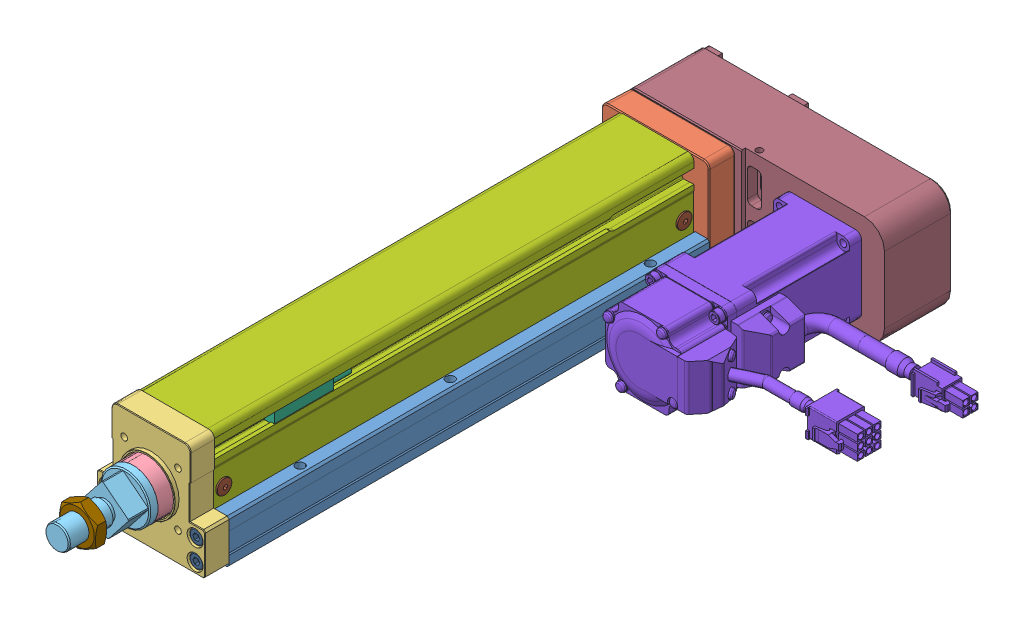
SolidWorks assembly CFY5-BR-100W, configuration Default. Lengths in mm.
Overall size (197.79 55.75 350).
25 component instances, 14 part files, 57 mates.
Components (placement in the parent):
- 底座GY5^CFY5-BR-100W-1: 底座GY5^CFY5-BR-100W [默认] at (172.2343 500.0265 205.4117) x (1 0 0) z (0 -1 0) size (54 240 25) (virtual)
- 丝杆座板GY5^CFY5-BR-100W-1: 丝杆座板GY5^CFY5-BR-100W [默认] at (172.2343 515.5765 191.9117) size (54.09 55.09 28) (virtual)
- 轴承座Y5^CFY5-BR-100W-1: 轴承座Y5^CFY5-BR-100W [Default] at (172.2343 516.7765 445.4117) size (54 54 22) (virtual)
- 推杆Y5^CFY5-BR-100W-1: 推杆Y5^CFY5-BR-100W [Default] at (172.2343 516.7765 316.4117) x (-0.030388 -0.999538 0) z (-0.999538 0.030388 0) size (25 150 25) (virtual)
- 螺纹连接头Y5^CFY5-BR-100W-1: 螺纹连接头Y5^CFY5-BR-100W [Default] at (172.2343 516.7765 470.4117) x (-0.620248 -0.784406 0) z (0 0 -1) size (25 25 47) (virtual)
- 磁性感应开关^CFY5-BR-100W-2: 磁性感应开关^CFY5-BR-100W [默认] at (153.1454 533.4018 308.9117) x (-1 0 0) z (0 0 -1) size (5 6.3 39.5) (virtual)
- 上盖Y5^CFY5-BR-100W-1: 上盖Y5^CFY5-BR-100W [Default] at (153.6454 513.9765 205.4117) size (38.57 34 240) (virtual)
- 松下100W电机MSMF012L1U2^CFY5-BR-100W-1: 松下100W电机MSMF012L1U2^CFY5-BR-100W [默认] at (241.2343 516.7765 190.4117) x (0 0 -1) z (0 -1 0) size (118.87 120.84 38.2) (virtual)
- 磁性感应开关^CFY5-BR-100W-3: 磁性感应开关^CFY5-BR-100W [默认] at (153.1454 533.4018 269.4117) x (-1 0 0) z (0 0 -1) size (5 6.3 39.5) (virtual)
- 磁性感应开关^CFY5-BR-100W-4: 磁性感应开关^CFY5-BR-100W [默认] at (191.3174 533.4018 385.4117) x (1 0 0) z (0 0 -1) size (5 6.3 39.5) (virtual)
- 六角薄螺母M12×1.25^CFY5-BR-100W-1: 六角薄螺母M12×1.25^CFY5-BR-100W [默认] at (172.2343 516.7765 494.4117) x (0.828588 -0.559859 0) z (0 0 1) size (20.78 18 6) (virtual)
- hexagon socket head cap screws gb-6: hexagon socket head cap screws gb [GB_FASTENER_SCREWS_HSHCS M4X12-N] at (194.2343 504.2765 456.8117) x (0 0 -1) z (1 0 0) size (16 7 7)
- hexagon socket head cap screws gb-7: hexagon socket head cap screws gb [GB_FASTENER_SCREWS_HSHCS M4X12-N] at (194.2343 493.7765 456.8117) x (0 0 -1) z (1 0 0) size (16 7 7)
- hexagon socket head cap screws gb-8: hexagon socket head cap screws gb [GB_FASTENER_SCREWS_HSHCS M4X12-N] at (150.2343 493.7765 456.8117) x (0 0 -1) z (1 0 0) size (16 7 7)
- hexagon socket head cap screws gb-9: hexagon socket head cap screws gb [GB_FASTENER_SCREWS_HSHCS M4X12-N] at (150.2343 504.2765 456.8117) x (0 0 -1) z (1 0 0) size (16 7 7)
- 内六角螺丝M3X5^CFY5-BR-100W-1: 内六角螺丝M3X5^CFY5-BR-100W [默认] at (186.1785 516.7765 210.4117) x (0 -1 0) z (0 0 1) size (7.5 6.19 7.5) (virtual)
- 内六角螺丝M3X5^CFY5-BR-100W-2: 内六角螺丝M3X5^CFY5-BR-100W [默认] at (186.1785 516.7765 440.4117) x (0 -0.21215 -0.977237) z (0 -0.977237 0.21215) size (7.5 6.19 7.5) (virtual)
- 内六角螺丝M3X5^CFY5-BR-100W-3: 内六角螺丝M3X5^CFY5-BR-100W [默认] at (158.2843 516.7765 440.4117) x (0 0.554408 0.832245) z (0 -0.832245 0.554408) size (7.5 6.19 7.5) (virtual)
- 内六角螺丝M3X5^CFY5-BR-100W-4: 内六角螺丝M3X5^CFY5-BR-100W [默认] at (158.2843 516.7765 210.4117) x (0 -0.497668 -0.867368) z (0 0.867368 -0.497668) size (7.5 6.19 7.5) (virtual)
- 304电机盖板Y5^CFY5-BR-100W-1: 304电机盖板Y5^CFY5-BR-100W [默认] at (208.9843 516.7765 157.4117) x (0 -1 0) z (1 0 0) size (51.5 1 123.5) (virtual)
- 电机板Y5-BLRM-P38^CFY5-BR-100W-1: 电机板Y5-BLRM-P38^CFY5-BR-100W [默认] at (220.4343 516.0265 205.4117) x (0 0 1) z (0 -1 0) size (38 125.5 53.5) (virtual)
- hexagon socket button head screws gb-7: hexagon socket button head screws gb [GB_SOCKET_TYPE7 M3X6-N] at (265.2343 504.2765 154.7617) x (0 0 1) z (-1 0 0) size (7.65 5.7 5.7)
- hexagon socket button head screws gb-8: hexagon socket button head screws gb [GB_SOCKET_TYPE7 M3X6-N] at (265.2343 529.2765 154.7617) x (0 0 1) z (-1 0 0) size (7.65 5.7 5.7)
- hexagon socket button head screws gb-9: hexagon socket button head screws gb [GB_SOCKET_TYPE7 M3X6-N] at (152.2343 504.2765 154.7617) x (0 0 1) z (-1 0 0) size (7.65 5.7 5.7)
- hexagon socket button head screws gb-10: hexagon socket button head screws gb [GB_SOCKET_TYPE7 M3X6-N] at (152.2343 529.2765 154.7617) x (0 0 1) z (-1 0 0) size (7.65 5.7 5.7)
Mates (geometry in assembly coordinates):
- 同心129: concentric: cylinder of 推杆Y5^CFY5-BR-100W-1 through (172.2343 516.7765 466.4117) axis (0 0 -1) radius 8.5; cylinder of 螺纹连接头Y5^CFY5-BR-100W-1 through (172.2343 516.7765 457.4117) axis (0 0 1) radius 10
- 重合133: coincident: plane of 推杆Y5^CFY5-BR-100W-1 through (172.2343 516.7765 466.4117) normal (0 0 1); plane of 螺纹连接头Y5^CFY5-BR-100W-1 through (172.2343 516.7765 466.4117) normal (0 0 -1)
- 同心133: concentric: cylinder of 底座GY5^CFY5-BR-100W-1 through (194.2343 493.7765 445.4117) axis (0 0 1) radius 1.65; cylinder of 轴承座Y5^CFY5-BR-100W-1 through (194.2343 493.7765 457.4117) axis (0 0 1) radius 2.25
- 重合134: coincident: plane of 底座GY5^CFY5-BR-100W-1 through (167.2343 487.8265 445.4117) normal (0 0 1); plane of 轴承座Y5^CFY5-BR-100W-1 through (172.2343 516.7765 445.4117) normal (0 0 -1)
- 同心136: concentric: cylinder of 底座GY5^CFY5-BR-100W-1 through (150.2343 504.2765 445.4117) axis (0 0 1) radius 1.65; cylinder of 轴承座Y5^CFY5-BR-100W-1 through (150.2343 504.2765 457.4117) axis (0 0 1) radius 2.25
- 重合143: coincident: plane of 底座GY5^CFY5-BR-100W-1 through (167.2343 487.8265 445.4117) normal (0 0 1); plane of 上盖Y5^CFY5-BR-100W-1 through (158.1567 536.5769 445.4117) normal (0 0 1)
- 重合144: coincident: plane of 底座GY5^CFY5-BR-100W-1 through (190.0843 508.7765 445.4117) normal (0 1 0); plane of 上盖Y5^CFY5-BR-100W-1 through (191.1785 508.7765 445.4117) normal (0 -1 0)
- 宽度31: width: plane of 磁性感应开关^CFY5-BR-100W-2 through (158.1454 536.5518 338.4117) normal (0 1 0); plane of 磁性感应开关^CFY5-BR-100W-2 through (158.1454 530.2518 308.9117) normal (0 -1 0); plane of 上盖Y5^CFY5-BR-100W-1 through (158.1567 529.7267 445.4117) normal (0 1 0); plane of 上盖Y5^CFY5-BR-100W-1 through (154.9454 537.0769 445.4117) normal (0 -1 0)
- 重合148: coincident: plane of 磁性感应开关^CFY5-BR-100W-2 through (154.9454 536.5518 338.4117) normal (-1 0 0); plane of 上盖Y5^CFY5-BR-100W-1 through (154.9454 536.0769 445.4117) normal (1 0 0)
- 重合1579: coincident: plane of 底座GY5^CFY5-BR-100W-1 through (154.3843 512.7765 445.4117) normal (-1 0 0); plane of 上盖Y5^CFY5-BR-100W-1 through (154.3843 527.7267 445.4117) normal (1 0 0)
- 重合1583: coincident: line of 磁性感应开关^CFY5-BR-100W-2 through (158.1454 536.5518 338.4117) axis (0 0 -1); plane of 磁性感应开关^CFY5-BR-100W-3 through (158.1454 533.4018 269.4117) normal (1 0 0)
- 重合1586: coincident: plane of 磁性感应开关^CFY5-BR-100W-2 through (158.1454 536.5518 338.4117) normal (0 1 0); plane of 磁性感应开关^CFY5-BR-100W-3 through (158.1454 536.5518 298.9117) normal (0 1 0)
- 重合1603: coincident: plane of 磁性感应开关^CFY5-BR-100W-2 through (155.6454 533.4018 298.9117) normal (0 0 -1); plane of 磁性感应开关^CFY5-BR-100W-3 through (158.1454 530.2518 298.9117) normal (0 0 1)
- 距离9: distance = 30.5 mm: plane of 磁性感应开关^CFY5-BR-100W-4 through (186.3174 536.5518 414.9117) normal (0 0 1); plane of 轴承座Y5^CFY5-BR-100W-1 through (172.2343 516.7765 445.4117) normal (0 0 -1)
- 同心1661: concentric: cylinder of 底座GY5^CFY5-BR-100W-1 through (194.3343 506.7765 205.4117) axis (0 0 -1) radius 1.65; cylinder of 丝杆座板GY5^CFY5-BR-100W-1 through (194.3343 506.7765 192.4117) axis (0 0 -1) radius 4
- 同心1662: concentric: cylinder of 底座GY5^CFY5-BR-100W-1 through (150.1343 506.7765 205.4117) axis (0 0 -1) radius 1.65; cylinder of 丝杆座板GY5^CFY5-BR-100W-1 through (150.1343 506.7765 192.4117) axis (0 0 -1) radius 2.4
- 重合1605: coincident: plane of 底座GY5^CFY5-BR-100W-1 through (167.2343 487.8265 205.4117) normal (0 0 -1); plane of 丝杆座板GY5^CFY5-BR-100W-1 through (172.2343 515.5765 205.4117) normal (0 0 1)
- 距离11: distance = 64 mm: plane of 磁性感应开关^CFY5-BR-100W-3 through (158.1454 536.5518 269.4117) normal (0 0 -1); plane of 丝杆座板GY5^CFY5-BR-100W-1 through (172.2343 515.5765 205.4117) normal (0 0 1)
- 同心1672: concentric: cylinder of 螺纹连接头Y5^CFY5-BR-100W-1 through (172.2343 516.7765 504.4117) axis (0 0 -1) radius 6; cylinder of 六角薄螺母M12×1.25^CFY5-BR-100W-1 through (172.2343 516.7765 488.4117) axis (0 0 1) radius 5.3235
- 距离12: distance = 8 mm: plane of 螺纹连接头Y5^CFY5-BR-100W-1 through (172.2343 516.7765 480.4117) normal (0 0 1); plane of 六角薄螺母M12×1.25^CFY5-BR-100W-1 through (162.8901 512.2283 488.4117) normal (0 0 -1)
- 重合1616: coincident: plane of 上盖Y5^CFY5-BR-100W-1 through (189.5174 529.7267 445.4117) normal (-1 0 0); plane of 磁性感应开关^CFY5-BR-100W-4 through (189.5174 530.2518 414.9117) normal (1 0 0)
- 宽度33: width: plane of 上盖Y5^CFY5-BR-100W-1 through (189.5174 530.7267 445.4117) normal (0 1 0); plane of 上盖Y5^CFY5-BR-100W-1 through (189.5174 536.0769 445.4117) normal (0 -1 0); plane of 磁性感应开关^CFY5-BR-100W-4 through (191.3174 535.9018 414.9117) normal (0 1 0); plane of 磁性感应开关^CFY5-BR-100W-4 through (189.5174 530.9018 414.9117) normal (0 -1 0)
- 同心1673: concentric: cylinder of 轴承座Y5^CFY5-BR-100W-1 through (172.2343 516.7765 457.4117) axis (0 0 -1) radius 13.25; cylinder of 推杆Y5^CFY5-BR-100W-1 through (172.2343 516.7765 466.4117) axis (0 0 -1) radius 12.5
- 距离13: distance = 47 mm: plane of 螺纹连接头Y5^CFY5-BR-100W-1 through (172.2343 516.7765 504.4117) normal (0 0 1); plane of 轴承座Y5^CFY5-BR-100W-1 through (172.2343 516.7765 457.4117) normal (0 0 1)
- 同心1674: concentric: cylinder of 轴承座Y5^CFY5-BR-100W-1 through (194.2343 504.2765 457.4117) axis (0 0 1) radius 2.25; cylinder of hexagon socket head cap screws gb-6 through (194.2343 504.2765 440.8117) axis (0 0 1) radius 2
- 重合1618: coincident: plane of 轴承座Y5^CFY5-BR-100W-1 through (196.4843 504.2765 452.8117) normal (0 0 1); plane of hexagon socket head cap screws gb-6 through (194.2343 504.2765 452.8117) normal (0 0 -1)
- 同心1675: concentric: cylinder of 轴承座Y5^CFY5-BR-100W-1 through (194.2343 493.7765 457.4117) axis (0 0 1) radius 4; cylinder of hexagon socket head cap screws gb-7 through (194.2343 493.7765 440.8117) axis (0 0 1) radius 2
- 重合1619: coincident: plane of 轴承座Y5^CFY5-BR-100W-1 through (196.4843 493.7765 452.8117) normal (0 0 1); plane of hexagon socket head cap screws gb-7 through (194.2343 493.7765 452.8117) normal (0 0 -1)
- 同心1676: concentric: cylinder of 轴承座Y5^CFY5-BR-100W-1 through (150.2343 493.7765 457.4117) axis (0 0 1) radius 2.25; cylinder of hexagon socket head cap screws gb-8 through (150.2343 493.7765 440.8117) axis (0 0 1) radius 2
- 重合1620: coincident: plane of 轴承座Y5^CFY5-BR-100W-1 through (152.4843 493.7765 452.8117) normal (0 0 1); plane of hexagon socket head cap screws gb-8 through (150.2343 493.7765 452.8117) normal (0 0 -1)
- 同心1677: concentric: cylinder of 轴承座Y5^CFY5-BR-100W-1 through (150.2343 504.2765 457.4117) axis (0 0 1) radius 2.25; cylinder of hexagon socket head cap screws gb-9 through (150.2343 504.2765 440.8117) axis (0 0 1) radius 2
- 重合1621: coincident: plane of 轴承座Y5^CFY5-BR-100W-1 through (152.4843 504.2765 452.8117) normal (0 0 1); plane of hexagon socket head cap screws gb-9 through (150.2343 504.2765 452.8117) normal (0 0 -1)
- 同心1678: concentric: cylinder of 丝杆座板GY5^CFY5-BR-100W-1 through (189.9843 516.7765 210.4117) axis (1 0 0) radius 1.25; cylinder of 内六角螺丝M3X5^CFY5-BR-100W-1 through (186.1785 516.7765 210.4117) axis (-1 0 0) radius 1.5
- 重合1622: coincident: plane of 上盖Y5^CFY5-BR-100W-1 through (191.1785 526.1852 445.4117) normal (1 0 0); circle of 内六角螺丝M3X5^CFY5-BR-100W-1
- 同心1679: concentric: cylinder of 上盖Y5^CFY5-BR-100W-1 through (153.2843 516.7765 440.4117) axis (-1 0 0) radius 1.75; cylinder of 内六角螺丝M3X5^CFY5-BR-100W-2 through (186.1785 516.7765 440.4117) axis (-1 0 0) radius 1.5
- 重合1623: coincident: plane of 上盖Y5^CFY5-BR-100W-1 through (191.1785 526.1852 445.4117) normal (1 0 0); plane of 内六角螺丝M3X5^CFY5-BR-100W-2 through (191.1785 516.7765 440.4117) normal (-1 0 0)
- 重合1624: coincident: plane of 上盖Y5^CFY5-BR-100W-1 through (153.2843 526.1852 445.4117) normal (-1 0 0); plane of 内六角螺丝M3X5^CFY5-BR-100W-3 through (153.2843 516.7765 440.4117) normal (1 0 0)
- 同心1680: concentric: cylinder of 上盖Y5^CFY5-BR-100W-1 through (153.2843 516.7765 440.4117) axis (-1 0 0) radius 1.75; cylinder of 内六角螺丝M3X5^CFY5-BR-100W-3 through (158.2843 516.7765 440.4117) axis (1 0 0) radius 1.5
- 同心1681: concentric: cylinder of 上盖Y5^CFY5-BR-100W-1 through (153.2843 516.7765 210.4117) axis (-1 0 0) radius 1.75; cylinder of 内六角螺丝M3X5^CFY5-BR-100W-4 through (158.2843 516.7765 210.4117) axis (1 0 0) radius 1.5
- 重合1625: coincident: plane of 上盖Y5^CFY5-BR-100W-1 through (153.2843 526.1852 445.4117) normal (-1 0 0); plane of 内六角螺丝M3X5^CFY5-BR-100W-4 through (153.2843 516.7765 210.4117) normal (1 0 0)
- 同心1691: concentric: cylinder of 304电机盖板Y5^CFY5-BR-100W-1 through (265.2343 504.2765 156.4117) axis (0 0 -1) radius 1.7; cylinder of hexagon socket button head screws gb-7 through (265.2343 504.2765 162.4117) axis (0 0 -1) radius 1.5
- 重合1631: coincident: plane of 304电机盖板Y5^CFY5-BR-100W-1 through (188.2343 492.0265 156.4117) normal (0 0 -1); plane of hexagon socket button head screws gb-7 through (265.2343 504.2765 156.4117) normal (0 0 1)
- 同心1692: concentric: cylinder of 304电机盖板Y5^CFY5-BR-100W-1 through (265.2343 529.2765 156.4117) axis (0 0 -1) radius 1.7; cylinder of hexagon socket button head screws gb-8 through (265.2343 529.2765 162.4117) axis (0 0 -1) radius 1.5
- 重合1632: coincident: plane of 304电机盖板Y5^CFY5-BR-100W-1 through (188.2343 492.0265 156.4117) normal (0 0 -1); plane of hexagon socket button head screws gb-8 through (265.2343 529.2765 156.4117) normal (0 0 1)
- 同心1693: concentric: cylinder of 304电机盖板Y5^CFY5-BR-100W-1 through (152.2343 504.2765 156.4117) axis (0 0 -1) radius 1.7; cylinder of hexagon socket button head screws gb-9 through (152.2343 504.2765 162.4117) axis (0 0 -1) radius 1.5
- 重合1633: coincident: plane of 304电机盖板Y5^CFY5-BR-100W-1 through (188.2343 492.0265 156.4117) normal (0 0 -1); plane of hexagon socket button head screws gb-9 through (152.2343 504.2765 156.4117) normal (0 0 1)
- 同心1694: concentric: cylinder of 304电机盖板Y5^CFY5-BR-100W-1 through (152.2343 529.2765 156.4117) axis (0 0 -1) radius 1.7; cylinder of hexagon socket button head screws gb-10 through (152.2343 529.2765 162.4117) axis (0 0 -1) radius 1.5
- 重合1634: coincident: plane of 304电机盖板Y5^CFY5-BR-100W-1 through (188.2343 492.0265 156.4117) normal (0 0 -1); plane of hexagon socket button head screws gb-10 through (152.2343 529.2765 156.4117) normal (0 0 1)
- 同心1695: concentric: cylinder of 丝杆座板GY5^CFY5-BR-100W-1 through (172.2343 516.7765 192.4117) axis (0 0 -1) radius 16; cylinder of 电机板Y5-BLRM-P38^CFY5-BR-100W-1 through (172.2343 516.7765 192.4117) axis (0 0 -1) radius 16
- 重合1635: coincident: plane of 丝杆座板GY5^CFY5-BR-100W-1 through (172.2343 516.7765 192.4117) normal (0 0 -1); plane of 电机板Y5-BLRM-P38^CFY5-BR-100W-1 through (220.4343 516.0265 192.4117) normal (0 0 1)
- 重合1636: coincident: plane of 304电机盖板Y5^CFY5-BR-100W-1 through (188.2343 492.0265 157.4117) normal (0 0 1); plane of 电机板Y5-BLRM-P38^CFY5-BR-100W-1 through (220.4343 516.0265 157.4117) normal (0 0 -1)
- 同心1697: concentric: cylinder of hexagon socket button head screws gb-9 through (152.2343 504.2765 162.4117) axis (0 0 -1) radius 1.5; cylinder of 电机板Y5-BLRM-P38^CFY5-BR-100W-1 through (152.2343 504.2765 157.4117) axis (0 0 -1) radius 1.25
- 同心1698: concentric: cylinder of hexagon socket button head screws gb-8 through (265.2343 529.2765 162.4117) axis (0 0 -1) radius 1.5; cylinder of 电机板Y5-BLRM-P38^CFY5-BR-100W-1 through (265.2343 529.2765 157.4117) axis (0 0 -1) radius 1.25
- 同心1699: concentric: cylinder of 松下100W电机MSMF012L1U2^CFY5-BR-100W-1 through (257.1442 500.8666 196.4117) axis (0 0 1) radius 1.7; cylinder of 电机板Y5-BLRM-P38^CFY5-BR-100W-1 through (257.1442 500.8666 192.4117) axis (0 0 1) radius 1.25
- 同心1700: concentric: cylinder of 松下100W电机MSMF012L1U2^CFY5-BR-100W-1 through (241.2343 516.7765 165.4117) axis (0 0 1) radius 4; cylinder of 电机板Y5-BLRM-P38^CFY5-BR-100W-1 through (241.2343 516.7765 179.4117) axis (0 0 1) radius 15
- 重合1637: coincident: plane of 松下100W电机MSMF012L1U2^CFY5-BR-100W-1 through (257.2343 500.7765 190.4117) normal (0 0 -1); plane of 电机板Y5-BLRM-P38^CFY5-BR-100W-1 through (220.4343 516.0265 190.4117) normal (0 0 1)
- 同心1701: concentric: cylinder of 丝杆座板GY5^CFY5-BR-100W-1 through (172.2343 537.2765 192.4117) axis (0 0 -1) radius 1.65; circle of 电机板Y5-BLRM-P38^CFY5-BR-100W-1
